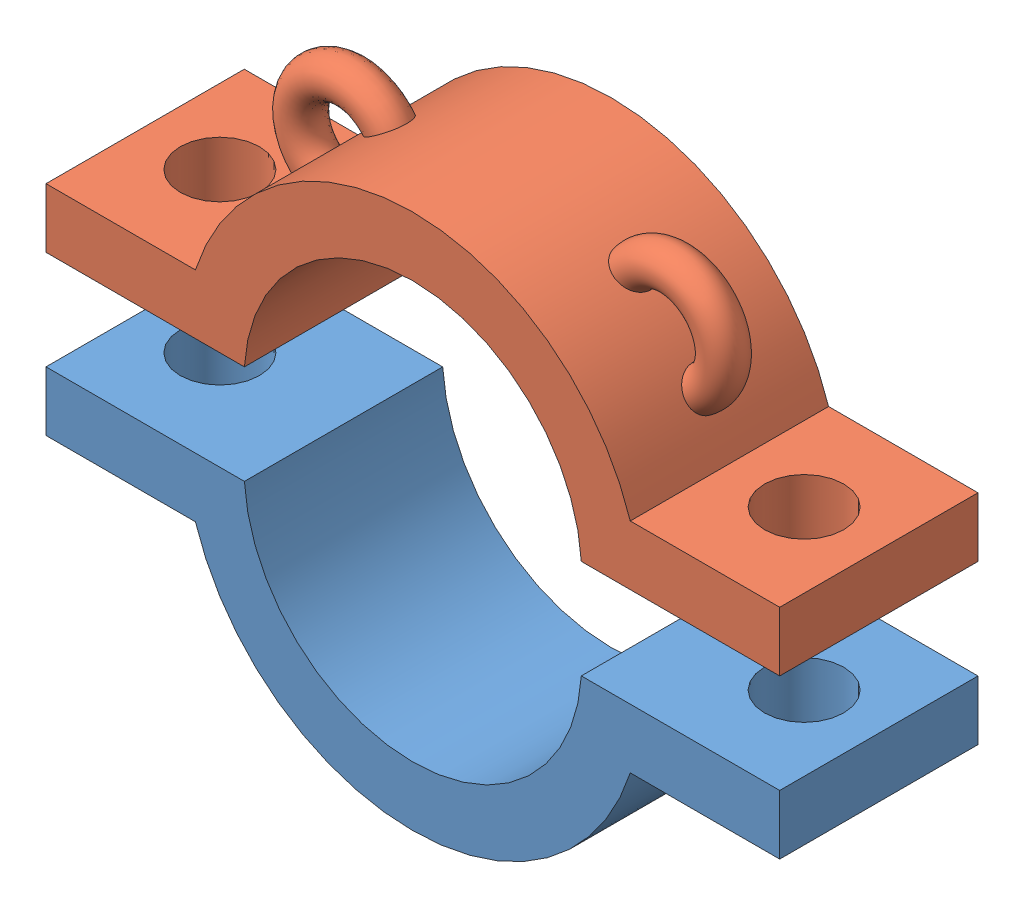
SolidWorks assembly Assem1, configuration Default. Lengths in mm.
Overall size (37 27.17 10).
2 component instances, 2 part files, 5 mates.
Components (placement in the parent):
- MordazaInferior-1: MordazaInferior [Default] at (-18.8415 57.5484 10) x (1 0 0) z (0 0 -1) size (37 11.01 10)
- MordazaSuperior-1: MordazaSuperior [Default] at (-18.8415 61.5484 10) x (-1 0 0) z (0 0 -1) size (37 11.16 10)
Mates (geometry in assembly coordinates):
- Parallel4: parallel anti-aligned: plane of MordazaSuperior-1 through (-10.3462 62.0484 0) normal (0 -1 0); plane of assembly through (0 0 0) normal (0 1 0)
- Coincident5: coincident aligned: plane of MordazaInferior-1 through (-18.8415 57.5484 0) normal (0 0 -1); plane of MordazaSuperior-1 through (-18.8415 61.5484 0) normal (0 0 -1)
- Coincident6: coincident anti-aligned: plane of MordazaSuperior-1 through (-18.8415 61.5484 0) normal (0 0 -1); plane of assembly through (0 0 0) normal (0 0 1)
- Coincident7: coincident aligned: plane of MordazaInferior-1 through (-37.3415 54.0482 0) normal (-1 0 0); plane of MordazaSuperior-1 through (-37.3415 65.0485 0) normal (-1 0 0)
- Distance1: distance = 5 mm anti-aligned: plane of MordazaInferior-1 through (-27.3368 57.0484 0) normal (0 1 0); plane of MordazaSuperior-1 through (-10.3462 62.0484 0) normal (0 -1 0)
